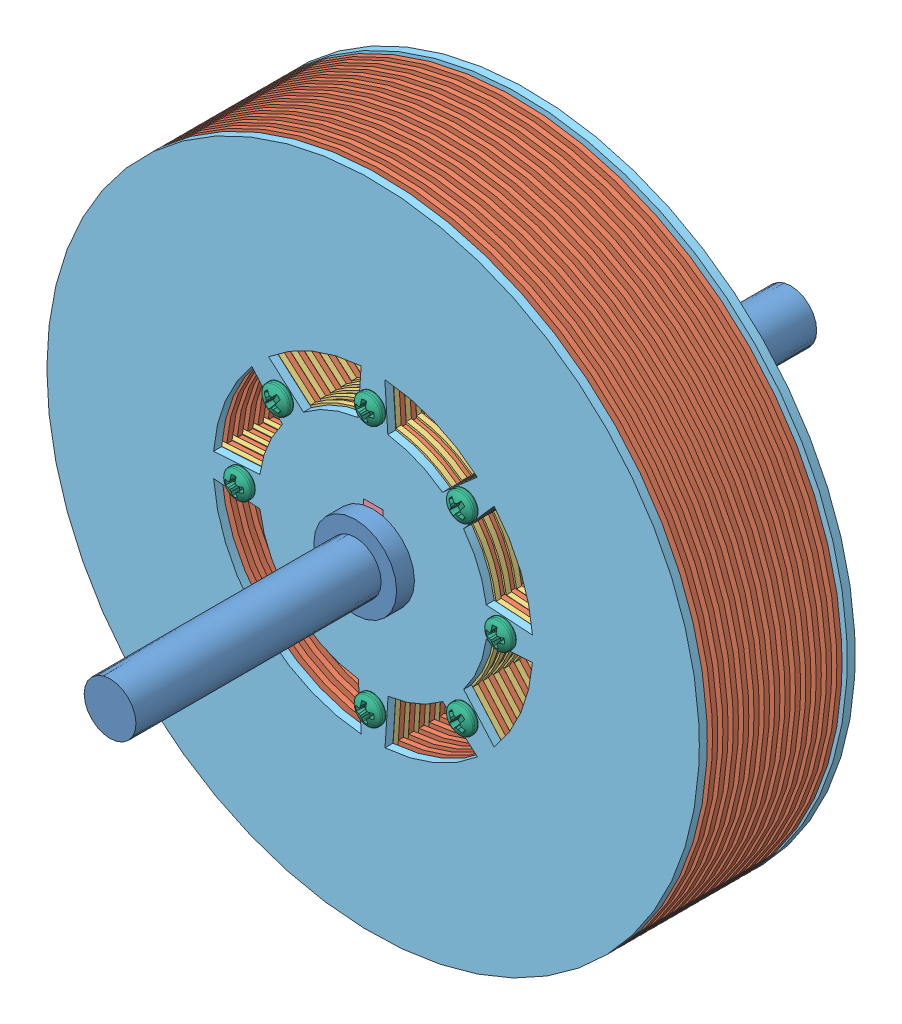
SolidWorks assembly rotor, configuration Default. Lengths in mm.
Overall size (101.6 101.6 165.52).
49 component instances, 8 part files, 30 mates.
Components (placement in the parent):
- axle-1: axle [Default] at origin size (11 11 165.52)
- disk 1-1: disk 1 [Default] at (0 0 117.18) size (100 100 0.8)
- spacer 1-2: spacer 1 [Default] at (-0.0407 0.0358 116.38) size (75.16 75.16 0.8)
- disk 1-2: disk 1 [Default] at (0 0 115.5925) size (100 100 0.8)
- disk 1-3: disk 1 [Default] at (0 0 114.005) size (100 100 0.8)
- disk 1-4: disk 1 [Default] at (0 0 112.4175) size (100 100 0.8)
- disk 1-5: disk 1 [Default] at (0 0 110.83) size (100 100 0.8)
- disk 1-6: disk 1 [Default] at (0 0 109.2425) size (100 100 0.8)
- disk 1-7: disk 1 [Default] at (0 0 107.655) size (100 100 0.8)
- disk 1-8: disk 1 [Default] at (0 0 106.0675) size (100 100 0.8)
- disk 1-9: disk 1 [Default] at (0 0 104.48) size (100 100 0.8)
- disk 1-10: disk 1 [Default] at (0 0 102.8925) size (100 100 0.8)
- disk 1-11: disk 1 [Default] at (0 0 101.305) size (100 100 0.8)
- disk 1-12: disk 1 [Default] at (0 0 99.7175) size (100 100 0.8)
- disk 1-13: disk 1 [Default] at (0 0 98.13) size (100 100 0.8)
- spacer 1-24: spacer 1 [Default] at (-0.0407 0.0358 114.7925) size (75.16 75.16 0.8)
- spacer 1-25: spacer 1 [Default] at (-0.0407 0.0358 113.205) size (75.16 75.16 0.8)
- spacer 1-26: spacer 1 [Default] at (-0.0407 0.0358 111.6175) size (75.16 75.16 0.8)
- spacer 1-27: spacer 1 [Default] at (-0.0407 0.0358 110.03) size (75.16 75.16 0.8)
- spacer 1-28: spacer 1 [Default] at (-0.0407 0.0358 108.4425) size (75.16 75.16 0.8)
- spacer 1-29: spacer 1 [Default] at (-0.0407 0.0358 106.855) size (75.16 75.16 0.8)
- spacer 1-30: spacer 1 [Default] at (-0.0407 0.0358 105.2675) size (75.16 75.16 0.8)
- spacer 1-31: spacer 1 [Default] at (-0.0407 0.0358 103.68) size (75.16 75.16 0.8)
- spacer 1-32: spacer 1 [Default] at (-0.0407 0.0358 102.0925) size (75.16 75.16 0.8)
- spacer 1-33: spacer 1 [Default] at (-0.0407 0.0358 100.505) size (75.16 75.16 0.8)
- spacer 1-34: spacer 1 [Default] at (-0.0407 0.0358 98.9175) size (75.16 75.16 0.8)
- spacer 1-35: spacer 1 [Default] at (-0.0407 0.0358 97.33) size (75.16 75.16 0.8)
- keyway-1: keyway [Default] at (-1.5 4 95.5) x (0 0 1) z (-1 0 0) size (24.5 3 3)
- keyway-2: keyway [Default] at (1.8837 -7 120.3326) x (0 0 -1) z (1 0 0) size (24.5 3 3)
- disk 0-1: disk 0 [Default] at (0 0 118.78) size (100 100 1.22)
- spacer 1-38: spacer 1 [Default] at (0 0 117.98) size (75.16 75.16 0.8)
- 92000A054_18-8 SS METRIC PAN HEAD PHIL MACHINE SCREW-1: 92000A054_18-8 SS METRIC PAN HEAD PHIL MACHINE SCREW [92000A054] at (0 20 90) x (-0.082915 0.996557 0) z (0 0 1) size (4.24 4.24 33.93)
- 94150A305_TYPE 316 STAINLESS STEEL HEX NUT-1: 94150A305_TYPE 316 STAINLESS STEEL HEX NUT [94150A305] at (0 20 95.31) x (0.98526 -0.171065 0) z (0 0 1) size (4 4.62 1.83)
- 94150A305_TYPE 316 STAINLESS STEEL HEX NUT-2: 94150A305_TYPE 316 STAINLESS STEEL HEX NUT [94150A305] at (-14.1421 14.1421 95.31) x (0.817645 0.575723 0) z (0 0 1) size (4 4.62 1.83)
- 94150A305_TYPE 316 STAINLESS STEEL HEX NUT-3: 94150A305_TYPE 316 STAINLESS STEEL HEX NUT [94150A305] at (-20 0 95.31) x (0.171065 0.98526 0) z (0 0 1) size (4 4.62 1.83)
- 94150A305_TYPE 316 STAINLESS STEEL HEX NUT-4: 94150A305_TYPE 316 STAINLESS STEEL HEX NUT [94150A305] at (-14.1421 -14.1421 95.31) x (-0.575723 0.817645 0) z (0 0 1) size (4 4.62 1.83)
- 94150A305_TYPE 316 STAINLESS STEEL HEX NUT-5: 94150A305_TYPE 316 STAINLESS STEEL HEX NUT [94150A305] at (0 -20 95.31) x (-0.98526 0.171065 0) z (0 0 1) size (4 4.62 1.83)
- 94150A305_TYPE 316 STAINLESS STEEL HEX NUT-6: 94150A305_TYPE 316 STAINLESS STEEL HEX NUT [94150A305] at (14.1421 -14.1421 95.31) x (-0.817645 -0.575723 0) z (0 0 1) size (4 4.62 1.83)
- 94150A305_TYPE 316 STAINLESS STEEL HEX NUT-7: 94150A305_TYPE 316 STAINLESS STEEL HEX NUT [94150A305] at (20 0 95.31) x (-0.171065 -0.98526 0) z (0 0 1) size (4 4.62 1.83)
- 94150A305_TYPE 316 STAINLESS STEEL HEX NUT-8: 94150A305_TYPE 316 STAINLESS STEEL HEX NUT [94150A305] at (14.1421 14.1421 95.31) x (0.575723 -0.817645 0) z (0 0 1) size (4 4.62 1.83)
- 92000A054_18-8 SS METRIC PAN HEAD PHIL MACHINE SCREW-2: 92000A054_18-8 SS METRIC PAN HEAD PHIL MACHINE SCREW [92000A054] at (-14.1421 14.1421 90) x (-0.763302 0.646042 0) z (0 0 1) size (4.24 4.24 33.93)
- 92000A054_18-8 SS METRIC PAN HEAD PHIL MACHINE SCREW-3: 92000A054_18-8 SS METRIC PAN HEAD PHIL MACHINE SCREW [92000A054] at (-20 0 90) x (-0.996557 -0.082915 0) z (0 0 1) size (4.24 4.24 33.93)
- 92000A054_18-8 SS METRIC PAN HEAD PHIL MACHINE SCREW-4: 92000A054_18-8 SS METRIC PAN HEAD PHIL MACHINE SCREW [92000A054] at (-14.1421 -14.1421 90) x (-0.646042 -0.763302 0) z (0 0 1) size (4.24 4.24 33.93)
- 92000A054_18-8 SS METRIC PAN HEAD PHIL MACHINE SCREW-5: 92000A054_18-8 SS METRIC PAN HEAD PHIL MACHINE SCREW [92000A054] at (0 -20 90) x (0.082915 -0.996557 0) z (0 0 1) size (4.24 4.24 33.93)
- 92000A054_18-8 SS METRIC PAN HEAD PHIL MACHINE SCREW-6: 92000A054_18-8 SS METRIC PAN HEAD PHIL MACHINE SCREW [92000A054] at (14.1421 -14.1421 90) x (0.763302 -0.646042 0) z (0 0 1) size (4.24 4.24 33.93)
- 92000A054_18-8 SS METRIC PAN HEAD PHIL MACHINE SCREW-7: 92000A054_18-8 SS METRIC PAN HEAD PHIL MACHINE SCREW [92000A054] at (20 0 90) x (0.996557 0.082915 0) z (0 0 1) size (4.24 4.24 33.93)
- 92000A054_18-8 SS METRIC PAN HEAD PHIL MACHINE SCREW-8: 92000A054_18-8 SS METRIC PAN HEAD PHIL MACHINE SCREW [92000A054] at (14.1421 14.1421 90) x (0.646042 0.763302 0) z (0 0 1) size (4.24 4.24 33.93)
- rotating part for simulation^rotor-1: rotating part for simulation^rotor [Default] at (0 0 120) size (101.6 101.6 30) (hidden, virtual)
- disk 0-2: disk 0 [Default] at (0 0 96.11) size (100 100 1.22)
Mates (geometry in assembly coordinates):
- Coincident3: coincident anti-aligned: plane of disk 1-1 through (0 0 117.18) normal (0 0 -1); plane of spacer 1-2 through (-0.0407 0.0358 117.18) normal (0 0 1)
- Coincident4: coincident aligned: plane of disk 1-1 through (13.8711 10.6697 117.98) normal (0.751594 -0.659626 0); plane of spacer 1-2 through (2.546 -2.2345 117.18) normal (0.751594 -0.659626 0)
- Coincident15: coincident aligned: plane of ? through (-1.5 7 94.2055) normal (1 0 0); plane of ? through (-1.5 0 95.031) normal (1 0 0)
- Concentric5: concentric aligned: circle of axle-1; circle of disk 1-1
- Coincident16: coincident aligned: plane of axle-1 through (-1.5 4 93) normal (1 0 0); plane of disk 1-1 through (-1.5 7 117.98) normal (1 0 0)
- Coincident17: coordinate: point of axle-1; point of assembly
- Coincident18: coincident anti-aligned: plane of axle-1 through (0 4 0) normal (0 1 0); plane of keyway-1 through (-1.5 4 95.5) normal (0 -1 0)
- Coincident19: coincident anti-aligned: plane of axle-1 through (1.5 4 120) normal (-1 0 0); plane of keyway-1 through (1.5 7 95.5) normal (1 0 0)
- Coincident21: coincident anti-aligned: plane of axle-1 through (0 -4 0) normal (0 -1 0); plane of keyway-2 through (1.8837 -4 120.3326) normal (0 1 0)
- Coincident22: coincident anti-aligned: plane of axle-1 through (1.8837 -4 120.0203) normal (-1 0 0); plane of keyway-2 through (1.8837 -4 120.3326) normal (1 0 0)
- Coincident25: coincident anti-aligned: plane of ? through (0 0 94.955) normal (0 0 -1); plane of 94150A305_TYPE 316 STAINLESS STEEL HEX NUT-1 through (-2 21.1547 94.955) normal (0 0 1)
- Concentric8: concentric aligned: circle of axle-1; circle of disk 0-1
- Coincident26: coincident anti-aligned: plane of axle-1 through (0 0 120) normal (0 0 -1); plane of disk 0-1 through (0 0 120) normal (0 0 1)
- Coincident27: coincident aligned: plane of axle-1 through (-1.5 4 93) normal (1 0 0); plane of disk 0-1 through (-1.5 7 120) normal (1 0 0)
- Concentric9: concentric anti-aligned: circle of axle-1; circle of spacer 1-38
- Coincident28: coincident anti-aligned: plane of disk 0-1 through (0 0 118.78) normal (0 0 -1); plane of spacer 1-38 through (0 0 118.78) normal (0 0 1)
- Coincident29: coincident aligned: plane of axle-1 through (-1.5 4 93) normal (1 0 0); plane of spacer 1-38 through (-1.5 0 118.78) normal (1 0 0)
- Concentric10: concentric anti-aligned: circle of disk 0-1; circle of 92000A054_18-8 SS METRIC PAN HEAD PHIL MACHINE SCREW-1
- Coincident34: coincident anti-aligned: plane of disk 0-1 through (0 0 120) normal (0 0 1); plane of 92000A054_18-8 SS METRIC PAN HEAD PHIL MACHINE SCREW-1 through (0 20 120) normal (0 0 -1)
- Coincident31: coincident anti-aligned: plane of disk 1-1 through (0 0 117.98) normal (0 0 1); plane of spacer 1-38 through (0 0 117.98) normal (0 0 -1)
- Concentric11: concentric anti-aligned: circle of 92000A054_18-8 SS METRIC PAN HEAD PHIL MACHINE SCREW-1; circle of 94150A305_TYPE 316 STAINLESS STEEL HEX NUT-1
- Coincident35: coincident anti-aligned: plane of axle-1 through (0 0 120) normal (0 0 -1); plane of keyway-1 through (-1.5 7 120) normal (0 0 1)
- InPlace1: in place: plane of disk 0-1 through (0 0 120) normal (0 0 1); plane of rotating part for simulation^rotor-1 through (0 0 120) normal (0 0 1); moOrthogonalPlaneRef_w of disk 0-1 through (0 0 120) normal (0 0 1); plane of rotating part for simulation^rotor-1 through (0 0 120) normal (0 1 0); plane of disk 0-1 through (0 0 120) normal (0 0 1); plane of rotating part for simulation^rotor-1 through (0 0 120) normal (1 0 0); plane of disk 0-1 through (0 0 120) normal (0 0 1); unknown of rotating part for simulation^rotor-1
- Coincident36: coincident aligned: plane of disk 0-1; plane of rotating part for simulation^rotor-1
- Coincident37: coincident aligned: moOrthogonalPlaneRef_w of disk 0-1 through (0 0 120) normal (0 1 0); plane of rotating part for simulation^rotor-1 through (0 0 120) normal (0 1 0)
- Coincident38: coincident anti-aligned: moOrthogonalPlaneRef_w of disk 0-1 through (0 0 120) normal (-1 0 0); plane of rotating part for simulation^rotor-1 through (0 0 120) normal (1 0 0)
- Concentric12: concentric aligned: cylinder of axle-1 through (0 0 93.36) axis (0 0 -1) radius 3.97; cylinder of disk 0-2 through (0 0 97.33) axis (0 0 -1) radius 5
- Coincident36: coincident anti-aligned: plane of keyway-1 through (1.5 7 95.5) normal (1 0 0); plane of disk 0-2 through (1.5 7 97.33) normal (-1 0 0)
- Coincident37: coincident anti-aligned: plane of spacer 1-35 through (-0.0407 0.0358 97.33) normal (0 0 -1); plane of disk 0-2 through (0 0 97.33) normal (0 0 1)
- Coincident38: coincident anti-aligned: plane of 94150A305_TYPE 316 STAINLESS STEEL HEX NUT-1 through (-1.773 21.4798 96.11) normal (0 0 1); plane of disk 0-2 through (0 0 96.11) normal (0 0 -1)
